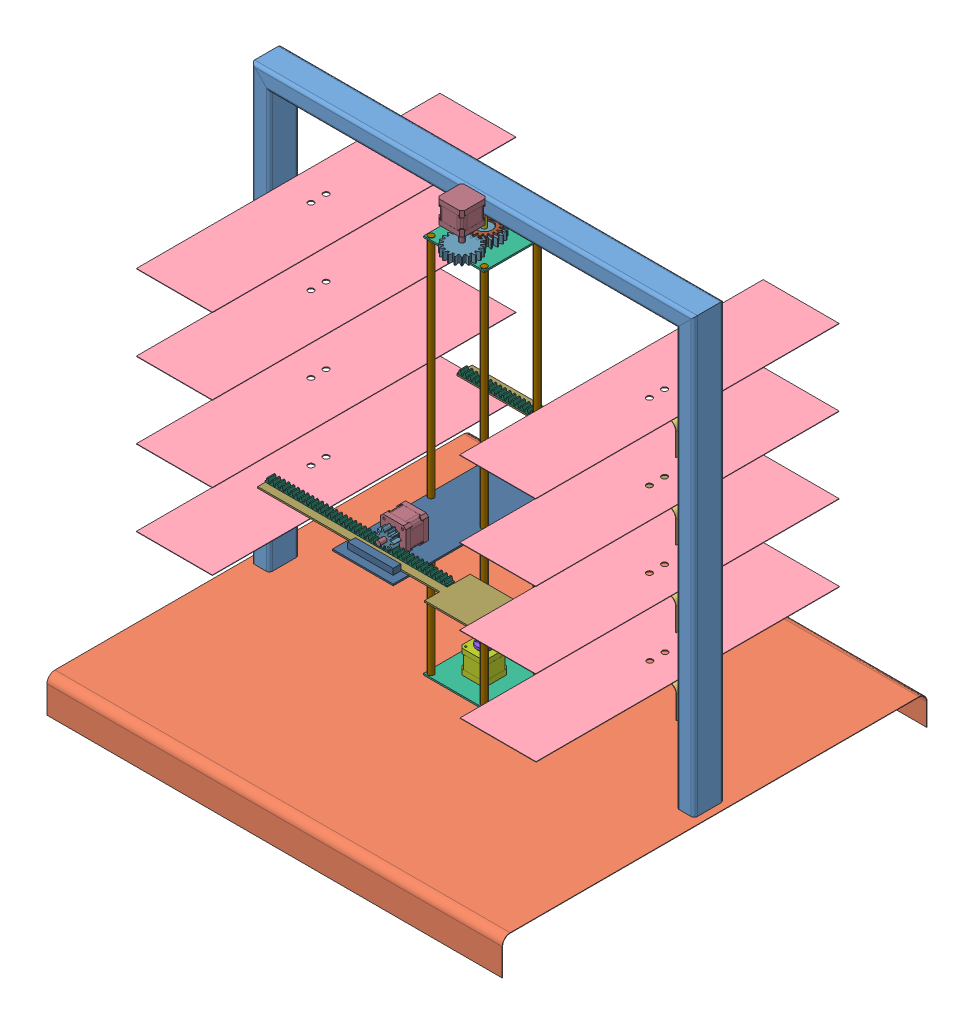
SolidWorks assembly Final assembly, configuration Default. Lengths in mm.
Overall size (762 787.67 711.2).
41 component instances, 15 part files, 107 mates.
Components (placement in the parent):
- Stand pillar-1: Stand pillar [Default<As Machined>] at (-19.6319 194.4293 842.7909) size (741.2 726.2 50)
- Base parking1-1: Base parking1 [Default] at (-46.144 191.8893 642.9461) x (0 0 -1) z (1 0 0) size (711.2 71.63 762)
- clamp-1: clamp [Default] at (647.3277 753.2166 817.196) size (101.6 50.8 50.8)
- clamp-2: clamp [Default] at (647.3277 626.2166 817.196) size (101.6 50.8 50.8)
- clamp-3: clamp [Default] at (647.3277 499.2166 817.196) size (101.6 50.8 50.8)
- clamp-5: clamp [Default] at (648.0643 372.2166 817.196) size (101.6 50.8 50.8)
- clamp-6: clamp [Default] at (24.6085 372.2166 868.3858) x (-1 0 0) z (0 0 -1) size (101.6 50.8 50.8)
- clamp-7: clamp [Default] at (24.6085 499.2166 868.3858) x (-1 0 0) z (0 0 -1) size (101.6 50.8 50.8)
- clamp-8: clamp [Default] at (24.6085 626.2166 868.3858) x (-1 0 0) z (0 0 -1) size (101.6 50.8 50.8)
- clamp-9: clamp [Default] at (24.6085 753.2166 868.3858) x (-1 0 0) z (0 0 -1) size (101.6 50.8 50.8)
- Parking plate-2: Parking plate [Default] at (542.8498 753.2166 1096.596) x (0 0 -1) z (0 -1 0) size (508 127 0.74)
- Parking plate-3: Parking plate [Default] at (542.8498 626.2166 1096.596) x (0 0 -1) z (0 -1 0) size (508 127 0.74)
- Parking plate-4: Parking plate [Default] at (542.8498 499.2166 1096.596) x (0 0 -1) z (0 -1 0) size (508 127 0.74)
- Parking plate-5: Parking plate [Default] at (543.5864 372.2166 1096.596) x (0 0 -1) z (0 -1 0) size (508 127 0.74)
- Parking plate-7: Parking plate [Default] at (129.0864 372.9532 1096.9858) x (0 0 -1) z (0 1 0) size (508 127 0.74)
- Parking plate-8: Parking plate [Default] at (129.0864 499.9532 1096.9858) x (0 0 -1) z (0 1 0) size (508 127 0.74)
- Parking plate-9: Parking plate [Default] at (129.0864 626.9532 1096.9858) x (0 0 -1) z (0 1 0) size (508 127 0.74)
- Parking plate-10: Parking plate [Default] at (129.0864 753.9532 1096.9858) x (0 0 -1) z (0 1 0) size (508 127 0.74)
- single row radial ball bearing_is-1: single row radial ball bearing_is [IS 6455 SR - 00-40-S] at (334.856 199.7256 842.9711) x (0.999213 0 -0.039669) z (0 1 0) size (68 68 9)
- New Upper 4 stans-2: New Upper 4 stans [Default] at (332.9839 206.7656 845.7608) x (1 0 0) z (0 -1 0) size (101.6 101.6 2.54)
- Motor screw-2: Motor screw [Valor predeterminado] at (333.0566 206.7656 845.7608) x (0.999991 0 -0.004234) z (0.004234 0 0.999991) size (42.1 699.4 42.1)
- Peça_Motor_Passo_r01-1: Peça_Motor_Passo_r01 [Valor predeterminado] at (333.0566 247.7656 845.7608) size (25 19.5 25)
- 4rod-1: 4rod [Default] at (288.6066 841.7656 890.2108) x (0.706576 0 -0.707638) z (0 -1 0) size (9.65 9.65 635)
- 4rod-2: 4rod [Default] at (377.4339 841.7656 890.2108) x (0.566686 0 0.823934) z (0 -1 0) size (9.65 9.65 635)
- 4rod-3: 4rod [Default] at (377.4339 841.7656 801.3108) x (0.706576 0 -0.707638) z (0 -1 0) size (9.65 9.65 635)
- 4rod-4: 4rod [Default] at (288.6066 841.7656 801.3108) x (0.706576 0 -0.707638) z (0 -1 0) size (9.65 9.65 635)
- New Upper 4 stans-4: New Upper 4 stans [Default] at (333.0566 838.4795 845.7608) x (-1 0 0) z (0 1 0) size (101.6 101.6 2.54)
- single row radial ball bearing_is-2: single row radial ball bearing_is [IS 6455 SR - 00-40-S] at (333.0566 833.9795 845.7608) x (0.999213 0 -0.039669) z (0 1 0) size (68 68 9)
- lifting plate-1: lifting plate [Default] at (333.0566 460.6671 845.7608) x (0 0 -1) z (0 -1 0) size (406.4 101.6 12.7)
- gear-1: gear [Default] at (333.0566 849.5895 845.7608) x (1 0 0) z (0 -1 0) size (46.72 46.32 15.6)
- slider-1: slider [Default] at (369.5921 463.2071 1024.2473) x (1 0 0) z (0 1 0) size (406.4 76.2 2.54)
- slider-2: slider [Default] at (372.9429 465.7471 667.2743) x (1 0 0) z (0 -1 0) size (406.4 76.2 2.54)
- stepper up-1: stepper up [Valor predeterminado] at (338.2983 890.6293 888.3369) x (0 0 -1) z (-1 0 0) size (42.3 63.4 42.3)
- spur gear_ai-2: spur gear_ai [Inch - Spur gear 10DP 20T 20PA 0.5FW ---S20N3.0H2.0L0.03125N] at (338.2983 853.7195 888.3369) x (0 -1 0) z (0 0 1) size (12.7 55.38 55.38)
- spur gear_ai-3: spur gear_ai [Inch - Spur gear 10DP 20T 20PA 0.5FW ---S20N3.0H2.0L0.03125N] at (333.0566 841.0195 845.7608) x (0 1 0) z (0 0 1) size (12.7 55.38 55.38)
- stepper up-2: stepper up [Valor predeterminado] at (328.6328 484.3071 701.3608) x (1 0 0) z (0 1 0) size (42.3 63.4 42.3)
- stepper up-3: stepper up [Valor predeterminado] at (333.0104 484.3071 990.1608) x (1 0 0) z (0 -1 0) size (42.3 63.4 42.3)
- spur gear_ai-4: spur gear_ai [Inch - Spur gear 10DP 10T 20PA 0.5FW ---S10N3.0H2.0L0.03125N] at (328.6328 484.3071 679.1608) x (0 0 1) z (-1 0 0) size (12.7 29.16 30.48)
- rack spur rectangular_ai-4: rack spur rectangular_ai [Inch - Rack-spur - rectangular 10DP 14.5PA 0.5FW .2PH 12L---SAll] at (135.7768 465.7471 693.3608) size (304.8 7.62 12.7)
- rack spur rectangular_ai-5: rack spur rectangular_ai [Inch - Rack-spur - rectangular 10DP 14.5PA 0.5FW .2PH 12L---SAll] at (131.1169 465.7471 1010.8608) size (304.8 7.62 12.7)
- spur gear_ai-5: spur gear_ai [Inch - Spur gear 10DP 10T 20PA 0.5FW ---S10N3.0H2.0L0.03125N] at (333.0104 484.3071 999.6608) x (0 0 1) z (-1 0 0) size (12.7 29.16 30.48)
Mates (geometry in assembly coordinates):
- Parallel1: parallel aligned: plane of Stand pillar-1 through (691.5681 920.6293 862.5909) normal (0 1 0); plane of Base parking1-1 through (715.856 191.8893 1198.5711) normal (0 1 0)
- Parallel2: parallel aligned: plane of Stand pillar-1 through (691.5681 915.4293 867.7909) normal (0 0 1); plane of Base parking1-1 through (-46.144 191.8893 1198.5711) normal (0 0 1)
- Coincident3: coincident: plane of Stand pillar-1 through (681.7681 194.4293 822.9909) normal (0 -1 0); plane of Base parking1-1 through (-46.144 204.5893 642.9461) normal (0 1 0)
- Coincident4: coincident: plane of Stand pillar-1 through (681.7681 194.4293 822.9909) normal (0 -1 0); plane of Base parking1-1 through (-46.144 204.5893 642.9461) normal (0 1 0)
- Parallel3: parallel aligned: plane of Base parking1-1 through (715.856 191.8893 1198.5711) normal (0 1 0); plane of clamp-1 through (574.9681 753.2166 867.996) normal (0 1 0)
- Parallel4: parallel aligned: plane of Stand pillar-1 through (676.5681 194.4293 822.9909) normal (-1 0 0); plane of clamp-1 through (675.8315 753.2166 867.996) normal (-1 0 0)
- Coincident8: coincident anti-aligned: plane of Stand pillar-1 through (676.5681 194.4293 822.9909) normal (-1 0 0); plane of clamp-1 through (676.5681 753.2166 867.996) normal (1 0 0)
- Coincident9: coincident anti-aligned: plane of Stand pillar-1 through (676.5681 194.4293 822.9909) normal (-1 0 0); plane of clamp-2 through (676.5681 626.2166 867.996) normal (1 0 0)
- Concentric2: concentric: circle of Stand pillar-1; circle of clamp-1
- Coincident13: coincident anti-aligned: plane of Stand pillar-1 through (676.5681 194.4293 822.9909) normal (-1 0 0); plane of clamp-3 through (676.5681 499.2166 867.996) normal (1 0 0)
- Concentric4: concentric: circle of Stand pillar-1; circle of clamp-3
- Coincident17: coincident: circle of Stand pillar-1; circle of clamp-5
- Concentric6: concentric: circle of Stand pillar-1; circle of clamp-5
- Parallel8: parallel anti-aligned: plane of Stand pillar-1 through (-4.6319 905.6293 822.9909) normal (1 0 0); plane of clamp-6 through (-4.6319 372.2166 817.5858) normal (-1 0 0)
- Parallel9: parallel aligned: plane of Base parking1-1 through (715.856 191.8893 1198.5711) normal (0 1 0); plane of clamp-6 through (96.9681 372.2166 817.5858) normal (0 1 0)
- Concentric10: concentric: cylinder of Stand pillar-1 through (-133.9179 340.0983 830.0909) axis (1 0 0) radius 4.826; cylinder of clamp-6 through (-2.0919 340.0983 830.0909) axis (-1 0 0) radius 4.826
- Coincident26: coincident: circle of Stand pillar-1; circle of clamp-6
- Coincident29: coincident anti-aligned: plane of Stand pillar-1 through (-4.6319 905.6293 822.9909) normal (1 0 0); plane of clamp-7 through (-4.6319 499.2166 817.5858) normal (-1 0 0)
- Concentric14: concentric: circle of Stand pillar-1; circle of clamp-7
- Coincident30: coincident anti-aligned: plane of Stand pillar-1 through (-4.6319 905.6293 822.9909) normal (1 0 0); plane of clamp-8 through (-4.6319 626.2166 817.5858) normal (-1 0 0)
- Concentric15: concentric: circle of Stand pillar-1; circle of clamp-8
- Coincident31: coincident anti-aligned: plane of Stand pillar-1 through (-4.6319 905.6293 822.9909) normal (1 0 0); plane of clamp-9 through (-4.6319 753.2166 817.5858) normal (-1 0 0)
- Coincident32: coincident: circle of Stand pillar-1; circle of clamp-9
- Coincident39: coincident anti-aligned: plane of clamp-1 through (574.9681 753.2166 867.996) normal (0 1 0); plane of Parking plate-2 through (542.8498 753.2166 1096.596) normal (0 -1 0)
- Concentric18: concentric aligned: circle of clamp-1; circle of Parking plate-2
- Concentric19: concentric aligned: circle of clamp-1; circle of Parking plate-2
- Coincident42: coincident anti-aligned: plane of clamp-2 through (574.9681 626.2166 867.996) normal (0 1 0); plane of Parking plate-3 through (542.8498 626.2166 1096.596) normal (0 -1 0)
- Concentric20: concentric aligned: circle of clamp-2; circle of Parking plate-3
- Concentric21: concentric aligned: circle of clamp-2; circle of Parking plate-3
- Coincident45: coincident anti-aligned: plane of clamp-3 through (574.9681 499.2166 867.996) normal (0 1 0); plane of Parking plate-4 through (542.8498 499.2166 1096.596) normal (0 -1 0)
- Concentric22: concentric aligned: circle of clamp-3; circle of Parking plate-4
- Concentric23: concentric aligned: circle of clamp-3; circle of Parking plate-4
- Coincident48: coincident anti-aligned: plane of clamp-5 through (575.7047 372.2166 867.996) normal (0 1 0); plane of Parking plate-5 through (543.5864 372.2166 1096.596) normal (0 -1 0)
- Concentric24: concentric aligned: circle of clamp-5; circle of Parking plate-5
- Concentric25: concentric aligned: circle of clamp-5; circle of Parking plate-5
- Concentric27: concentric: cylinder of Stand pillar-1 through (-133.9179 721.0983 855.4909) axis (1 0 0) radius 4.826; circle of clamp-9
- Concentric28: concentric: cylinder of Stand pillar-1 through (-133.9179 594.0983 855.4909) axis (1 0 0) radius 4.826; cylinder of clamp-8 through (-2.0919 594.0983 855.4909) axis (-1 0 0) radius 4.826
- Concentric29: concentric: circle of Stand pillar-1; circle of clamp-7
- Coincident54: coincident anti-aligned: plane of clamp-6 through (96.9681 372.2166 817.5858) normal (0 1 0); plane of Parking plate-7 through (129.0864 372.2166 1096.9858) normal (0 -1 0)
- Concentric30: concentric aligned: circle of clamp-6; circle of Parking plate-7
- Concentric31: concentric aligned: circle of clamp-6; circle of Parking plate-7
- Coincident57: coincident anti-aligned: plane of clamp-7 through (96.9681 499.2166 817.5858) normal (0 1 0); plane of Parking plate-8 through (129.0864 499.2166 1096.9858) normal (0 -1 0)
- Concentric32: concentric anti-aligned: circle of clamp-7; circle of Parking plate-8
- Coincident59: coincident anti-aligned: circle of clamp-7; circle of Parking plate-8
- Coincident60: coincident anti-aligned: plane of clamp-8 through (96.9681 626.2166 817.5858) normal (0 1 0); plane of Parking plate-9 through (129.0864 626.2166 1096.9858) normal (0 -1 0)
- Concentric33: concentric anti-aligned: circle of clamp-8; circle of Parking plate-9
- Concentric34: concentric anti-aligned: circle of clamp-8; circle of Parking plate-9
- Coincident63: coincident anti-aligned: plane of clamp-9 through (96.9681 753.2166 817.5858) normal (0 1 0); plane of Parking plate-10 through (129.0864 753.2166 1096.9858) normal (0 -1 0)
- Coincident64: coincident anti-aligned: plane of clamp-9 through (96.9681 753.2166 817.5858) normal (0 1 0); plane of Parking plate-10 through (129.0864 753.2166 1096.9858) normal (0 -1 0)
- Concentric35: concentric anti-aligned: circle of clamp-9; circle of Parking plate-10
- Concentric36: concentric anti-aligned: circle of clamp-9; circle of Parking plate-10
- Concentric37: concentric: circle of Stand pillar-1; circle of clamp-2
- Concentric38: concentric: circle of Stand pillar-1; circle of clamp-3
- Lock13: lock: unknown of Base parking1-1; unknown of single row radial ball bearing_is-1
- Coincident70: coincident anti-aligned: plane of single row radial ball bearing_is-1 through (333.5072 204.2256 808.9978) normal (0 1 0); plane of New Upper 4 stans-2 through (332.9839 204.2256 845.7608) normal (0 -1 0)
- Lock15: lock: unknown of single row radial ball bearing_is-1; unknown of New Upper 4 stans-2
- Coincident73: coincident: axis of single row radial ball bearing_is-1 through (334.856 219.3744 842.9711) axis (0 -1 0); line of Motor screw-2 through (334.856 752.7656 842.9711) axis (0 -1 0)
- Coincident75: coincident anti-aligned: plane of New Upper 4 stans-2 through (332.9839 206.7656 845.7608) normal (0 1 0); plane of Motor screw-2 through (333.0566 206.7656 845.7608) normal (0 -1 0)
- Coincident77: coincident anti-aligned: plane of Motor screw-2 through (333.0566 247.7656 845.7608) normal (0 1 0); moEndPointRef_w of Peça_Motor_Passo_r01-1
- Coincident81: coincident: line of Motor screw-2 through (334.856 752.7656 842.9711) axis (0 -1 0); line of Peça_Motor_Passo_r01-1 through (334.856 251.5656 842.9711) axis (0 -1 0)
- Coincident82: coincident aligned: line of New Upper 4 stans-2 through (288.6066 204.2256 890.2108) axis (0 1 0); line of 4rod-1 through (288.6066 206.7656 890.2108) axis (0 1 0)
- Concentric40: concentric anti-aligned: circle of New Upper 4 stans-2; circle of 4rod-1
- Coincident84: coincident anti-aligned: plane of New Upper 4 stans-2 through (332.9839 206.7656 845.7608) normal (0 1 0); plane of 4rod-1 through (288.6066 206.7656 890.2108) normal (0 -1 0)
- Coincident87: coincident anti-aligned: plane of New Upper 4 stans-2 through (332.9839 206.7656 845.7608) normal (0 1 0); plane of 4rod-2 through (377.4339 206.7656 890.2108) normal (0 -1 0)
- Coincident89: coincident aligned: line of New Upper 4 stans-2 through (377.4339 204.2256 890.2108) axis (0 1 0); line of 4rod-2 through (377.4339 206.7656 890.2108) axis (0 1 0)
- Coincident90: coincident anti-aligned: plane of New Upper 4 stans-2 through (332.9839 206.7656 845.7608) normal (0 1 0); plane of 4rod-3 through (377.4339 206.7656 801.3108) normal (0 -1 0)
- Coincident91: coincident aligned: line of New Upper 4 stans-2 through (377.4339 204.2256 801.3108) axis (0 1 0); line of 4rod-3 through (377.4339 206.7656 801.3108) axis (0 1 0)
- Coincident92: coincident anti-aligned: plane of New Upper 4 stans-2 through (332.9839 206.7656 845.7608) normal (0 1 0); plane of 4rod-4 through (288.6066 206.7656 801.3108) normal (0 -1 0)
- Coincident93: coincident aligned: line of New Upper 4 stans-2 through (288.6066 204.2256 801.3108) axis (0 1 0); line of 4rod-4 through (288.6066 206.7656 801.3108) axis (0 1 0)
- Coincident98: coincident anti-aligned: line of 4rod-2 through (377.4339 206.7656 890.2108) axis (0 1 0); line of New Upper 4 stans-4 through (377.4339 841.0195 890.2108) axis (0 -1 0)
- Coincident99: coincident anti-aligned: line of Motor screw-2 through (333.0566 906.1656 845.7608) axis (0 -1 0); line of New Upper 4 stans-4 through (333.0566 838.4795 845.7608) axis (0 1 0)
- Coincident100: coincident anti-aligned: line of 4rod-1 through (288.6066 206.7656 890.2108) axis (0 1 0); line of New Upper 4 stans-4 through (288.6066 841.0195 890.2108) axis (0 -1 0)
- Lock18: lock: unknown of 4rod-3; unknown of New Upper 4 stans-4
- Lock19: lock: unknown of Motor screw-2; unknown of New Upper 4 stans-4
- Lock20: lock: unknown of 4rod-4; unknown of New Upper 4 stans-4
- Coincident101: coincident aligned: line of Motor screw-2 through (333.0566 906.1656 845.7608) axis (0 -1 0); line of Peça_Motor_Passo_r01-1 through (333.0566 267.2656 845.7608) axis (0 -1 0)
- Coincident102: coincident aligned: line of Motor screw-2 through (333.0566 906.1656 845.7608) axis (0 -1 0); line of single row radial ball bearing_is-2 through (333.0566 853.6283 845.7608) axis (0 -1 0)
- Coincident103: coincident anti-aligned: plane of New Upper 4 stans-4 through (333.0566 838.4795 845.7608) normal (0 -1 0); plane of single row radial ball bearing_is-2 through (331.7079 838.4795 811.7876) normal (0 1 0)
- Coincident104: coincident aligned: line of Motor screw-2 through (333.0566 906.1656 845.7608) axis (0 -1 0); line of lifting plate-1 through (333.0566 463.2071 845.7608) axis (0 -1 0)
- Coincident105: coincident anti-aligned: line of 4rod-4 through (288.6066 206.7656 801.3108) axis (0 1 0); line of lifting plate-1 through (288.6066 463.2071 801.3108) axis (0 -1 0)
- Coincident110: coincident anti-aligned: line of single row radial ball bearing_is-2 through (333.0566 853.6283 845.7608) axis (0 -1 0); line of gear-1 through (333.0566 843.0195 845.7608) axis (0 1 0)
- Coincident112: coincident anti-aligned: plane of New Upper 4 stans-4 through (333.0566 841.0195 845.7608) normal (0 1 0); plane of gear-1 through (333.0566 841.0195 845.7608) normal (0 -1 0)
- Coincident113: coincident anti-aligned: plane of lifting plate-1 through (333.0566 463.2071 845.7608) normal (0 1 0); plane of slider-1 through (369.5921 463.2071 1024.2473) normal (0 -1 0)
- Coincident114: coincident anti-aligned: plane of lifting plate-1 through (371.1566 473.3671 1023.5608) normal (0 0 -1); plane of slider-1 through (131.6083 465.7471 1023.5608) normal (0 0 1)
- Coincident115: coincident anti-aligned: plane of lifting plate-1 through (371.1566 473.3671 667.9608) normal (0 0 1); plane of slider-2 through (134.959 463.2071 667.9608) normal (0 0 -1)
- Coincident116: coincident anti-aligned: plane of lifting plate-1 through (333.0566 463.2071 845.7608) normal (0 1 0); plane of slider-2 through (372.9429 463.2071 667.2743) normal (0 -1 0)
- Coincident123: coincident aligned: plane of Stand pillar-1 through (691.5681 920.6293 862.5909) normal (0 1 0); plane of stepper up-1 through (338.2983 920.6293 888.3369) normal (0 1 0)
- Parallel12: parallel anti-aligned: plane of Stand pillar-1 through (676.5681 194.4293 822.9909) normal (-1 0 0); plane of stepper up-1 through (359.3983 912.6293 903.2369) normal (1 0 0)
- Coincident126: coincident anti-aligned: plane of New Upper 4 stans-4 through (333.0566 841.0195 845.7608) normal (0 1 0); plane of spur gear_ai-2 through (338.2983 841.0195 888.3369) normal (0 -1 0)
- Concentric42: concentric anti-aligned: circle of stepper up-1; circle of spur gear_ai-2
- Coincident127: coincident anti-aligned: plane of New Upper 4 stans-4 through (333.0566 841.0195 845.7608) normal (0 1 0); plane of spur gear_ai-3 through (333.0566 841.0195 845.7608) normal (0 -1 0)
- Coincident128: coincident aligned: line of single row radial ball bearing_is-2 through (333.0566 853.6283 845.7608) axis (0 -1 0); line of spur gear_ai-3 through (333.0566 853.7195 845.7608) axis (0 -1 0)
- Lock21: lock: unknown of Stand pillar-1; unknown of stepper up-1
- Coincident129: coincident anti-aligned: plane of lifting plate-1 through (333.0566 463.2071 845.7608) normal (0 1 0); plane of stepper up-2 through (313.7328 463.2071 723.3608) normal (0 -1 0)
- Coincident130: coincident anti-aligned: plane of slider-2 through (134.959 463.2071 693.3608) normal (0 0 1); plane of stepper up-2 through (328.6328 484.3071 693.3608) normal (0 0 -1)
- Lock22: lock: unknown of lifting plate-1; unknown of stepper up-2
- Coincident132: coincident anti-aligned: plane of lifting plate-1 through (333.0566 463.2071 845.7608) normal (0 1 0); plane of stepper up-3 through (318.1104 463.2071 968.1608) normal (0 -1 0)
- Coincident133: coincident anti-aligned: plane of slider-1 through (131.6083 465.7471 998.1608) normal (0 0 -1); plane of stepper up-3 through (333.0104 484.3071 998.1608) normal (0 0 1)
- Lock23: lock: unknown of lifting plate-1; unknown of stepper up-3
- Coincident135: coincident anti-aligned: plane of stepper up-2 through (328.6328 484.3071 691.8608) normal (0 0 -1); plane of spur gear_ai-4 through (328.6328 484.3071 691.8608) normal (0 0 1)
- Concentric43: concentric aligned: circle of stepper up-2; circle of spur gear_ai-4
- Coincident136: coincident anti-aligned: plane of slider-2 through (372.9429 465.7471 667.2743) normal (0 1 0); plane of rack spur rectangular_ai-4 through (135.7768 465.7471 680.6608) normal (0 -1 0)
- Coincident137: coincident anti-aligned: plane of stepper up-2 through (328.6328 484.3071 693.3608) normal (0 0 -1); plane of rack spur rectangular_ai-4 through (135.7768 473.3671 693.3608) normal (0 0 1)
- Coincident138: coincident anti-aligned: plane of stepper up-3 through (333.0104 484.3071 998.1608) normal (0 0 1); plane of rack spur rectangular_ai-5 through (131.1169 473.3671 998.1608) normal (0 0 -1)
- Coincident139: coincident anti-aligned: plane of slider-1 through (369.5921 465.7471 1024.2473) normal (0 1 0); plane of rack spur rectangular_ai-5 through (131.1169 465.7471 998.1608) normal (0 -1 0)
- Coincident140: coincident anti-aligned: plane of stepper up-3 through (333.0104 484.3071 999.6608) normal (0 0 1); plane of spur gear_ai-5 through (333.0104 484.3071 999.6608) normal (0 0 -1)
- Concentric44: concentric aligned: circle of stepper up-3; circle of spur gear_ai-5
